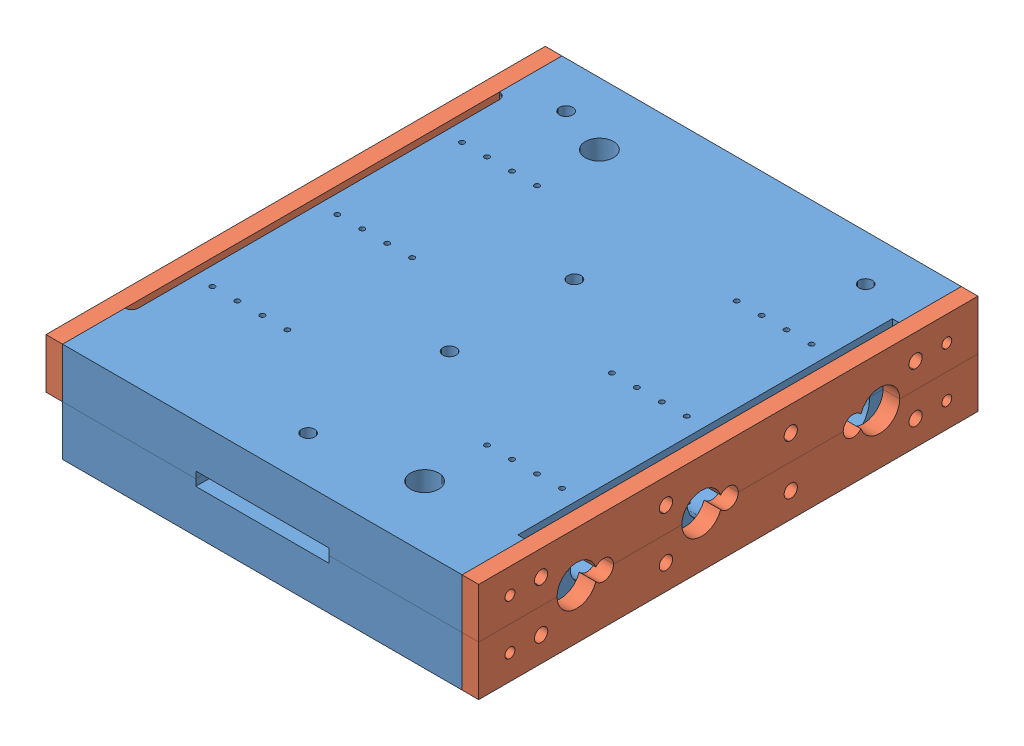
SolidWorks assembly assembly, configuration Default. Lengths in mm.
Overall size (130 30 150).
5 component instances, 2 part files, 13 mates.
Components (placement in the parent):
- top-bottom-1: top-bottom [Default] at (17.7949 66.9879 104.0361) size (120 15 150)
- top-bottom-2: top-bottom [Default] at (48.7402 96.9879 104.0361) x (-1 0 0) z (0 0 1) size (120 15 150)
- side-1: side [Default] at (98.2675 78.4348 128.4749) x (0 0 1) z (-1 0 0) size (150 15 5)
- side-3: side [Default] at (-26.7325 85.5409 164.8534) x (0 0 -1) z (-1 0 0) size (150 15 5)
- side-5: side [Default] at (93.2675 85.5409 128.4749) x (0 0 1) z (1 0 0) size (150 15 5)
Mates (geometry in assembly coordinates):
- Parallel2: parallel anti-aligned: line of top-bottom-1 through (93.2675 81.9879 221.6642) axis (0 -1 0); line of top-bottom-2 through (93.2675 81.9879 221.6642) axis (0 1 0)
- Coincident3: coincident anti-aligned: plane of top-bottom-1 through (17.7949 81.9879 104.0361) normal (0 1 0); plane of top-bottom-2 through (48.7402 81.9879 104.0361) normal (0 -1 0)
- Parallel3: parallel anti-aligned: line of top-bottom-1 through (-26.7325 66.9879 221.6642) axis (1 0 0); line of top-bottom-2 through (93.2675 96.9879 221.6642) axis (-1 0 0)
- Coincident4: coincident: point of top-bottom-1; point of top-bottom-2
- Coincident5: coincident: point of top-bottom-2; point of side-1
- Coincident6: coincident: point of top-bottom-2; point of side-1
- Coincident17: coincident: point of top-bottom-1; point of side-3
- Coincident18: coincident: point of top-bottom-2; point of side-3
- Coincident19: coincident: point of top-bottom-2; point of side-3
- Coincident23: coincident: plane of side-1 through (103.2675 81.9879 71.6642) normal (0 1 0); plane of side-5 through (88.2675 81.9879 71.6642) normal (0 -1 0)
- Coincident24: coincident: plane of side-1 through (103.2675 81.9879 71.6642) normal (0 1 0); plane of side-5 through (88.2675 81.9879 71.6642) normal (0 -1 0)
- Coincident25: coincident: line of side-1 through (98.2675 81.9879 221.6642) axis (-1 0 0); line of side-5 through (93.2675 81.9879 221.6642) axis (1 0 0)
- Coincident26: coincident: line of side-1 through (98.2675 81.9879 187.1642) axis (0 0 1); line of side-5 through (98.2675 81.9879 187.1642) axis (0 0 1)
